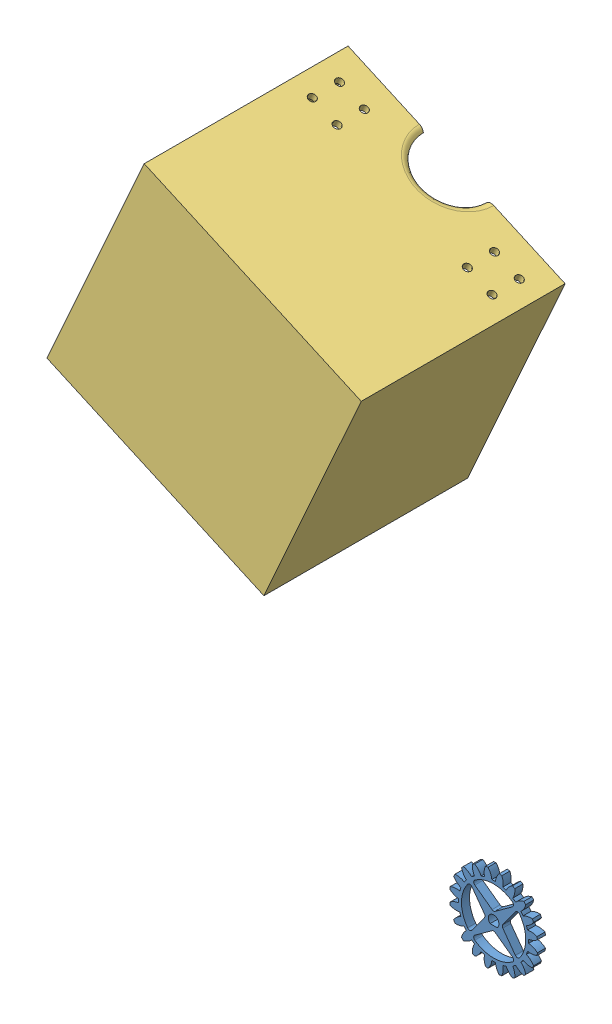
SolidWorks assembly Assem1 for gear box, configuration Default. Lengths in mm.
Overall size (121.88 257.7 76.2).
6 component instances, 3 part files, 7 mates.
Components (placement in the parent):
- first gear-1: first gear [1.0 30T] at (-135.5674 118.5995 60.8762) x (-0.238611 -0.971115 0) z (0.971115 -0.238611 0) size (32 3 31.89)
- Tempwall-1: Tempwall [Default] at (-132.2836 127.2844 60.8762) x (0.912479 -0.409124 0) z (0 0 1) size (83.82 50.8 7)
- first gear-2: first gear [1.5 10T] at (-135.5674 118.5995 57.8762) x (-0.485779 0.874082 0) z (-0.874082 -0.485779 0) size (18 3 17.3)
- first gear-3: first gear [1.5 20T] at (-80.4924 -49.6451 41.8412) x (1 0 0) z (0 1 0) size (32.73 3 32.73)
- first gear-4: first gear [1.0 20T] at (-111.6977 110.2081 57.8762) x (-0.870749 -0.491728 0) z (-0.491728 0.870749 0) size (21.82 3 21.82)
- Gear Box-1: Gear Box [Default] at (-127.2582 132.9461 27.1118) x (0.912479 -0.409124 0) z (0 0 1) size (88.9 88.9 76.2)
Mates (geometry in assembly coordinates):
- Coincident3: coincident anti-aligned: plane of first gear-1 through (-135.5674 118.5995 57.8762) normal (0 0 -1); plane of first gear-2 through (-135.5674 118.5995 57.8762) normal (0 0 1)
- Coincident4: coincident aligned: circle of first gear-1; circle of first gear-2
- Coincident26: coincident anti-aligned: plane of first gear-1 through (-135.5674 118.5995 60.8762) normal (0 0 1); plane of Tempwall-1 through (-132.2836 127.2844 60.8762) normal (0 0 -1)
- Coincident30: coincident anti-aligned: plane of Tempwall-1 through (-132.2836 127.2844 60.8762) normal (0 0 -1); plane of first gear-4 through (-111.6977 110.2081 60.8762) normal (0 0 1)
- Coincident32: coincident anti-aligned: plane of Tempwall-1 through (-161.863 158.2044 67.8762) normal (-0.912479 0.409124 0); plane of Gear Box-1 through (-147.3146 190.6522 103.3118) normal (0.912479 -0.409124 0)
- Coincident33: coincident anti-aligned: plane of Tempwall-1 through (-182.6465 111.8505 67.8762) normal (-0.409124 -0.912479 0); plane of Gear Box-1 through (-184.9642 112.8897 103.3118) normal (0.409124 0.912479 0)
- Parallel1: parallel: plane of first gear-1 through (-135.5674 118.5995 57.8762) normal (0 0 -1); line of Tempwall-1 through (-85.3791 123.9116 60.8762) axis (-0.912479 0.409124 0)
